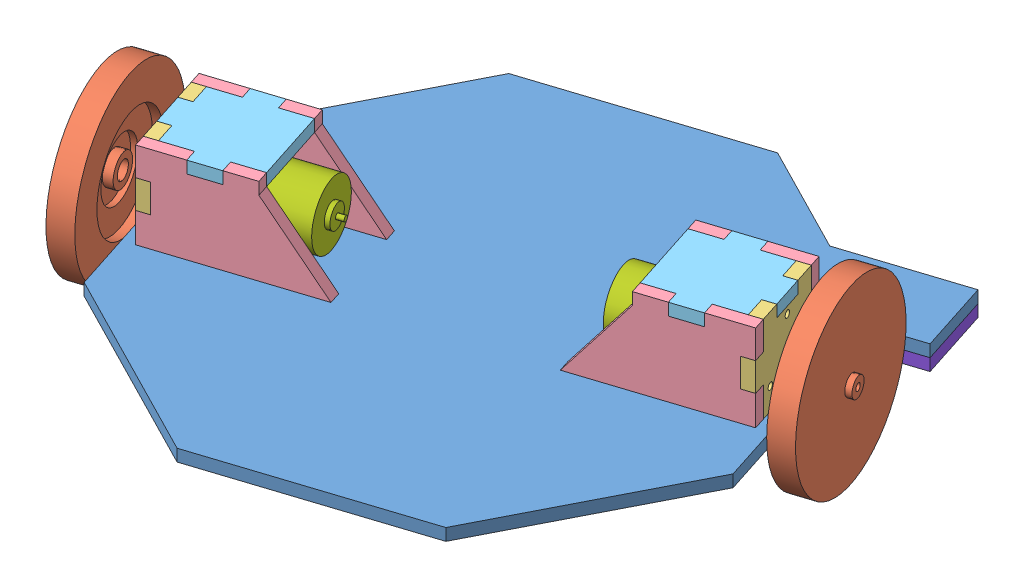
SolidWorks assembly Platform, configuration Default. Lengths in mm.
Overall size (287.09 101.22 246.65).
17 component instances, 8 part files, 50 mates.
Components (placement in the parent):
- base-1: base [Default] at (-14.3254 9.7548 0.932) size (246.65 5.33 246.65)
- Wheel-1: Wheel [Default] at (-130.7128 22.3278 38.5735) x (-0.951476 0 0.307722) z (-0.123421 -0.916044 -0.381616) size (12.7 76.2 76.2)
- Wheel-2: Wheel [Default] at (101.1941 22.3278 -36.4287) x (0.951476 0 -0.307722) z (-0.279043 -0.421555 -0.862802) size (12.7 76.2 76.2)
- motorMountFront-1: motorMountFront [Default] at (84.5197 28.9318 -31.036) x (0.951476 0 -0.307722) z (0.307722 0 0.951476) size (5.33 43.69 43.69)
- motorMountSide-1: motorMountSide [Default] at (49.2298 28.9318 -36.9747) x (-0.307722 0 -0.951476) z (0.951476 0 -0.307722) size (5.33 43.69 68.83)
- motorMountSide-2: motorMountSide [Default] at (61.0322 28.9318 -0.4818) x (-0.307722 0 -0.951476) z (0.951476 0 -0.307722) size (5.33 43.69 68.83)
- motorMountFront-2: motorMountFront [Default] at (-118.2457 28.9318 34.5414) x (0.951476 0 -0.307722) z (0.307722 0 0.951476) size (5.33 43.69 43.69)
- motorMountSide-3: motorMountSide [Default] at (-89.683 28.9318 2.3458) x (0.307722 0 0.951476) z (-0.951476 0 0.307722) size (5.33 43.69 68.83)
- motorMountSide-4: motorMountSide [Default] at (-77.8806 28.9318 38.8387) x (0.307722 0 0.951476) z (-0.951476 0 0.307722) size (5.33 43.69 68.83)
- motorMountTop-1: motorMountTop [Default] at (-95.0449 48.1088 27.0379) x (0.307722 0 0.951476) z (-0.951476 0 0.307722) size (43.69 5.33 43.43)
- motorMountTop-2: motorMountTop [Default] at (66.394 48.1088 -25.1739) x (-0.307722 0 -0.951476) z (0.951476 0 -0.307722) size (43.69 5.33 43.43)
- tapeSensor_TCRT5000-1: tapeSensor_TCRT5000 [Default] at (93.0517 7.0878 -89.0543) x (-0.307722 0 -0.951476) z (-0.951476 0 0.307722) size (10.16 7.29 4.45)
- tapeSensor_TCRT5000-2: tapeSensor_TCRT5000 [Default] at (73.3177 7.0878 -98.6892) x (-0.307722 0 -0.951476) z (-0.951476 0 0.307722) size (10.16 7.29 4.45)
- tapeSensor_TCRT5000-3: tapeSensor_TCRT5000 [Default] at (62.9631 7.0878 -79.3232) x (-0.307722 0 -0.951476) z (-0.951476 0 0.307722) size (10.16 7.29 4.45)
- 12V65RPMGearheadMotor-1: 12V65RPMGearheadMotor [Default] at (65.4901 28.9318 -24.8815) x (0.951476 0 -0.307722) z (0.307722 0 0.951476) size (70.26 33.02 33.02)
- 12V65RPMGearheadMotor-2: 12V65RPMGearheadMotor [Default] at (-94.141 28.9318 26.7456) x (-0.951476 0 0.307722) z (-0.307722 0 -0.951476) size (70.26 33.02 33.02)
- SideTapeSensorStand-1: SideTapeSensorStand [Default] at (72.5208 1.7538 -90.4229) x (0.951476 0 -0.307722) z (0.307722 0 0.951476) size (52.83 5.33 33.02)
Mates (geometry in assembly coordinates):
- Width5: width anti-aligned: plane of base-1 through (-4.4508 12.4218 -122.3907) normal (-0.307722 0 -0.951476); plane of base-1 through (-24.2001 12.4218 124.2547) normal (0.307722 0 0.951476); cylinder of Wheel-2 through (110.8611 22.3278 -39.5552) axis (-0.951476 0 0.307722) radius 38.1
- Width6: width anti-aligned: plane of base-1 through (-24.2001 12.4218 124.2547) normal (0.307722 0 0.951476); plane of base-1 through (-4.4508 12.4218 -122.3907) normal (-0.307722 0 -0.951476); cylinder of Wheel-1 through (-140.3798 22.3278 41.6999) axis (0.951476 0 -0.307722) radius 38.1
- Coincident14: coincident aligned: plane of motorMountFront-1 through (84.5143 45.4418 -48.3862) normal (0.951476 0 -0.307722); plane of motorMountSide-2 through (94.6753 13.0568 -16.9685) normal (0.951476 0 -0.307722)
- Coincident19: coincident aligned: plane of motorMountFront-1 through (84.5143 45.4418 -48.3862) normal (0.951476 0 -0.307722); plane of motorMountSide-1 through (82.873 13.0568 -53.4614) normal (0.951476 0 -0.307722)
- Width8: width anti-aligned: plane of motorMountSide-1 through (17.379 45.4418 -32.2797) normal (-0.307722 0 -0.951476); plane of motorMountSide-2 through (30.8228 45.4418 9.2884) normal (0.307722 0 0.951476); plane of base-1 through (-24.2001 12.4218 124.2547) normal (0.307722 0 0.951476); plane of base-1 through (-4.4508 12.4218 -122.3907) normal (-0.307722 0 -0.951476)
- Distance2: distance = 5.08 mm aligned: plane of motorMountFront-1 through (84.5143 45.4418 -48.3862) normal (0.951476 0 -0.307722); plane of base-1 through (108.9973 12.4218 10.8067) normal (0.951476 0 -0.307722)
- Coincident23: coincident anti-aligned: plane of base-1 through (-64.067 12.4218 -152.869) normal (0 1 0); plane of motorMountSide-2 through (89.6001 12.4218 -15.3271) normal (0 -1 0)
- Coincident24: coincident anti-aligned: plane of motorMountSide-2 through (89.6001 45.4418 -15.3271) normal (0 1 0); plane of motorMountTop-2 through (43.1879 45.4418 -35.0206) normal (0 -1 0)
- Coincident25: coincident aligned: plane of motorMountFront-1 through (84.5143 45.4418 -48.3862) normal (0.951476 0 -0.307722); plane of motorMountTop-2 through (91.8355 45.4418 -25.7493) normal (0.951476 0 -0.307722)
- Coincident26: coincident aligned: plane of motorMountSide-2 through (30.8228 45.4418 9.2884) normal (0.307722 0 0.951476); plane of motorMountTop-2 through (79.1578 45.4418 -6.3439) normal (0.307722 0 0.951476)
- Coincident27: coincident aligned: plane of motorMountFront-1 through (91.2415 28.9318 -10.2519) normal (0.307722 0 0.951476); plane of motorMountSide-2 through (30.8228 45.4418 9.2884) normal (0.307722 0 0.951476)
- Coincident28: coincident aligned: plane of motorMountFront-1 through (77.7978 28.9318 -51.82) normal (-0.307722 0 -0.951476); plane of motorMountSide-1 through (17.379 45.4418 -32.2797) normal (-0.307722 0 -0.951476)
- Coincident29: coincident aligned: plane of motorMountFront-1 through (69.688 50.7758 -76.8954) normal (0 1 0); plane of motorMountSide-1 through (77.7978 50.7758 -51.82) normal (0 1 0)
- Coincident30: coincident aligned: plane of motorMountFront-1 through (69.688 50.7758 -76.8954) normal (0 1 0); plane of motorMountSide-2 through (89.6001 50.7758 -15.3271) normal (0 1 0)
- Coincident31: coincident anti-aligned: plane of motorMountSide-4 through (-47.6712 45.4418 29.0686) normal (-0.307722 0 -0.951476); plane of motorMountTop-1 through (-108.09 50.7758 48.6089) normal (0.307722 0 0.951476)
- Coincident32: coincident aligned: plane of motorMountSide-4 through (-70.1974 45.4418 41.9599) normal (0.951476 0 -0.307722); plane of motorMountTop-1 through (-81.9997 50.7758 5.4669) normal (0.951476 0 -0.307722)
- Coincident33: coincident aligned: plane of motorMountSide-4 through (-106.4486 50.7758 53.6841) normal (0 1 0); plane of motorMountTop-1 through (-71.8387 50.7758 36.8847) normal (0 1 0)
- Coincident34: coincident anti-aligned: plane of motorMountSide-3 through (-57.8322 45.4418 -2.3492) normal (0.307722 0 0.951476); plane of motorMountTop-1 through (-118.251 50.7758 17.1912) normal (-0.307722 0 -0.951476)
- Coincident35: coincident aligned: plane of motorMountSide-3 through (-118.251 50.7758 17.1912) normal (0 1 0); plane of motorMountTop-1 through (-71.8387 50.7758 36.8847) normal (0 1 0)
- Coincident36: coincident aligned: plane of motorMountSide-3 through (-123.3261 13.0568 18.8325) normal (-0.951476 0 0.307722); plane of motorMountTop-1 through (-120.4863 45.4418 27.6134) normal (-0.951476 0 0.307722)
- Coincident38: coincident aligned: plane of motorMountFront-2 through (-124.9675 28.9318 13.7574) normal (-0.307722 0 -0.951476); plane of motorMountSide-3 through (-59.4736 45.4418 -7.4244) normal (-0.307722 0 -0.951476)
- Coincident39: coincident aligned: plane of motorMountFront-2 through (-133.0773 50.7758 -11.3181) normal (0 1 0); plane of motorMountTop-1 through (-71.8387 50.7758 36.8847) normal (0 1 0)
- Coincident40: coincident aligned: plane of motorMountFront-2 through (-123.3261 45.4418 18.8325) normal (-0.951476 0 0.307722); plane of motorMountSide-3 through (-123.3261 13.0568 18.8325) normal (-0.951476 0 0.307722)
- Distance3: distance = 5.08 mm aligned: plane of motorMountFront-2 through (-123.3261 45.4418 18.8325) normal (-0.951476 0 0.307722); plane of base-1 through (-137.6481 12.4218 -8.9426) normal (-0.951476 0 0.307722)
- Coincident41: coincident aligned: plane of base-1 through (-64.067 7.0878 -152.869) normal (0 -1 0); plane of motorMountSide-3 through (-118.251 7.0878 17.1912) normal (0 -1 0)
- Width9: width anti-aligned: plane of motorMountSide-3 through (-59.4736 45.4418 -7.4244) normal (-0.307722 0 -0.951476); plane of motorMountSide-4 through (-46.0299 45.4418 34.1437) normal (0.307722 0 0.951476); plane of base-1 through (-24.2001 12.4218 124.2547) normal (0.307722 0 0.951476); plane of base-1 through (-4.4508 12.4218 -122.3907) normal (-0.307722 0 -0.951476)
- Coincident42: coincident anti-aligned: plane of motorMountFront-1 through (79.4392 45.4418 -46.7449) normal (-0.951476 0 0.307722); plane of 12V65RPMGearheadMotor-1 through (84.5197 28.9318 -31.036) normal (0.951476 0 -0.307722)
- Width10: width anti-aligned: plane of base-1 through (-24.2001 12.4218 124.2547) normal (0.307722 0 0.951476); plane of base-1 through (-4.4508 12.4218 -122.3907) normal (-0.307722 0 -0.951476); cylinder of 12V65RPMGearheadMotor-1 through (34.5557 28.9318 -14.8769) axis (0.951476 0 -0.307722) radius 13.6906
- Parallel1: parallel anti-aligned: plane of base-1 through (-64.067 12.4218 -152.869) normal (0 1 0); plane of 12V65RPMGearheadMotor-1 through (86.8921 20.8278 -37.7324) normal (0 -1 0)
- Tangent1: tangent anti-aligned: plane of base-1 through (-64.067 12.4218 -152.869) normal (0 1 0); cylinder of 12V65RPMGearheadMotor-1 through (84.5197 28.9318 -31.036) axis (-0.951476 0 0.307722) radius 16.51
- Coincident44: coincident anti-aligned: plane of motorMountFront-2 through (-118.251 45.4418 17.1912) normal (0.951476 0 -0.307722); plane of 12V65RPMGearheadMotor-2 through (-113.1705 28.9318 32.9) normal (-0.951476 0 0.307722)
- Parallel2: parallel anti-aligned: plane of base-1 through (-64.067 12.4218 -152.869) normal (0 1 0); plane of 12V65RPMGearheadMotor-2 through (-115.543 20.8278 39.5964) normal (0 -1 0)
- Width11: width anti-aligned: plane of base-1 through (-24.2001 12.4218 124.2547) normal (0.307722 0 0.951476); plane of base-1 through (-4.4508 12.4218 -122.3907) normal (-0.307722 0 -0.951476); cylinder of 12V65RPMGearheadMotor-2 through (-63.2066 28.9318 16.7409) axis (-0.951476 0 0.307722) radius 13.6906
- Tangent2: tangent anti-aligned: plane of base-1 through (-64.067 12.4218 -152.869) normal (0 1 0); cylinder of 12V65RPMGearheadMotor-2 through (-113.1705 28.9318 32.9) axis (0.951476 0 -0.307722) radius 16.51
- Concentric1: concentric aligned: cylinder of Wheel-1 through (-136.7547 22.3278 40.5275) axis (0.951476 0 -0.307722) radius 3.81; cylinder of 12V65RPMGearheadMotor-2 through (-125.2542 22.3278 36.8081) axis (0.951476 0 -0.307722) radius 2.5
- Concentric2: concentric anti-aligned: cylinder of Wheel-2 through (101.1941 22.3278 -36.4287) axis (0.951476 0 -0.307722) radius 1.524; cylinder of 12V65RPMGearheadMotor-1 through (96.6034 22.3278 -34.944) axis (-0.951476 0 0.307722) radius 2.5
- Coincident45: coincident aligned: plane of tapeSensor_TCRT5000-2 through (73.8691 7.0878 -104.2067) normal (0 1 0); plane of tapeSensor_TCRT5000-3 through (63.5145 7.0878 -84.8406) normal (0 1 0)
- Coincident46: coincident aligned: plane of tapeSensor_TCRT5000-1 through (93.6031 7.0878 -94.5717) normal (0 1 0); plane of tapeSensor_TCRT5000-2 through (73.8691 7.0878 -104.2067) normal (0 1 0)
- Distance4: distance = 27.178 mm anti-aligned: plane of tapeSensor_TCRT5000-3 through (66.641 3.989 -75.1736) normal (0.951476 0 -0.307722); plane of tapeSensor_TCRT5000-1 through (92.5002 3.989 -83.5369) normal (-0.951476 0 0.307722)
- Coincident47: coincident aligned: plane of tapeSensor_TCRT5000-1 through (89.3738 3.989 -93.2039) normal (-0.307722 0 -0.951476); plane of tapeSensor_TCRT5000-3 through (59.2852 3.989 -83.4728) normal (-0.307722 0 -0.951476)
- Width12: width aligned: plane of tapeSensor_TCRT5000-2 through (76.9956 3.989 -94.5397) normal (0.951476 0 -0.307722); plane of tapeSensor_TCRT5000-2 through (72.7663 3.989 -93.1718) normal (-0.951476 0 0.307722); plane of tapeSensor_TCRT5000-3 through (66.641 3.989 -75.1736) normal (0.951476 0 -0.307722); plane of tapeSensor_TCRT5000-1 through (92.5002 3.989 -83.5369) normal (-0.951476 0 0.307722)
- Parallel3: parallel anti-aligned: plane of base-1 through (108.9973 12.4218 10.8067) normal (0.951476 0 -0.307722); plane of tapeSensor_TCRT5000-3 through (62.4117 3.989 -73.8058) normal (-0.951476 0 0.307722)
- Distance6: distance = 5.08 mm anti-aligned: plane of tapeSensor_TCRT5000-2 through (72.7663 3.989 -93.1718) normal (0.307722 0 0.951476); plane of tapeSensor_TCRT5000-1 through (89.3738 3.989 -93.2039) normal (-0.307722 0 -0.951476)
- Coincident51: coincident aligned: plane of base-1 through (92.5745 7.0878 -114.2606) normal (-0.307722 0 -0.951476); plane of SideTapeSensorStand-1 through (42.3061 7.0878 -98.003) normal (-0.307722 0 -0.951476)
- Coincident52: coincident aligned: plane of base-1 through (102.7355 7.0878 -82.8428) normal (0.951476 0 -0.307722); plane of SideTapeSensorStand-1 through (102.7355 7.0878 -82.8428) normal (0.951476 0 -0.307722)
- Width13: width aligned: plane of tapeSensor_TCRT5000-2 through (69.6398 3.989 -102.8388) normal (-0.307722 0 -0.951476); plane of tapeSensor_TCRT5000-1 through (92.5002 3.989 -83.5369) normal (0.307722 0 0.951476); plane of SideTapeSensorStand-1 through (42.3061 7.0878 -98.003) normal (-0.307722 0 -0.951476); plane of SideTapeSensorStand-1 through (52.4671 7.0878 -66.5852) normal (0.307722 0 0.951476)
- Distance7: distance = 5.08 mm aligned: plane of tapeSensor_TCRT5000-1 through (96.7295 3.989 -84.9047) normal (0.951476 0 -0.307722); plane of SideTapeSensorStand-1 through (102.7355 7.0878 -82.8428) normal (0.951476 0 -0.307722)
- Coincident54: coincident aligned: plane of base-1 through (102.7355 7.0878 -82.8428) normal (0.951476 0 -0.307722); plane of SideTapeSensorStand-1 through (102.7355 7.0878 -82.8428) normal (0.951476 0 -0.307722)
- Coincident56: coincident aligned: plane of tapeSensor_TCRT5000-1 through (93.6031 7.0878 -94.5717) normal (0 1 0); plane of SideTapeSensorStand-1 through (92.5745 7.0878 -114.2606) normal (0 1 0)
- Coincident57: coincident anti-aligned: plane of base-1 through (-64.067 7.0878 -152.869) normal (0 -1 0); plane of SideTapeSensorStand-1 through (92.5745 7.0878 -114.2606) normal (0 1 0)
